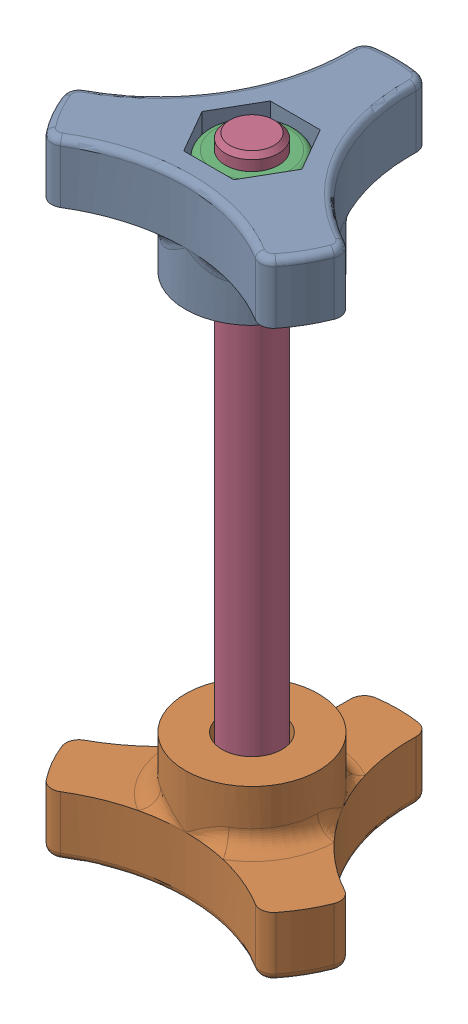
SolidWorks assembly TR23-RC-0700_60mm, configuration Default. Lengths in mm.
Overall size (41.18 95.3 36.41).
4 component instances, 4 part files, 0 mates.
Components (placement in the parent):
- TR23-RC-0050-1: TR23-RC-0050 [Default] at origin size (41.18 17 36.41)
- TR23-RC-0051-1: TR23-RC-0051 [Default] at (0 -60 0) x (-1 0 0) z (0 0 1) size (41.18 17 36.41)
- ISO 10511 M8 Locking Nut-1: ISO 10511 M8 Locking Nut [Default] at (0 9 0) x (0 0 -1) z (1 0 0) size (13 6.76 15.01)
- ISO 4017 - M8 x 90-N_ISO 4017 - M8 x 90-N-1: ISO 4017 - M8 x 90-N_ISO 4017 - M8 x 90-N [Default] at (0 -77.3 0) x (0 1 0) z (0 0 1) size (95.3 15.01 13)
